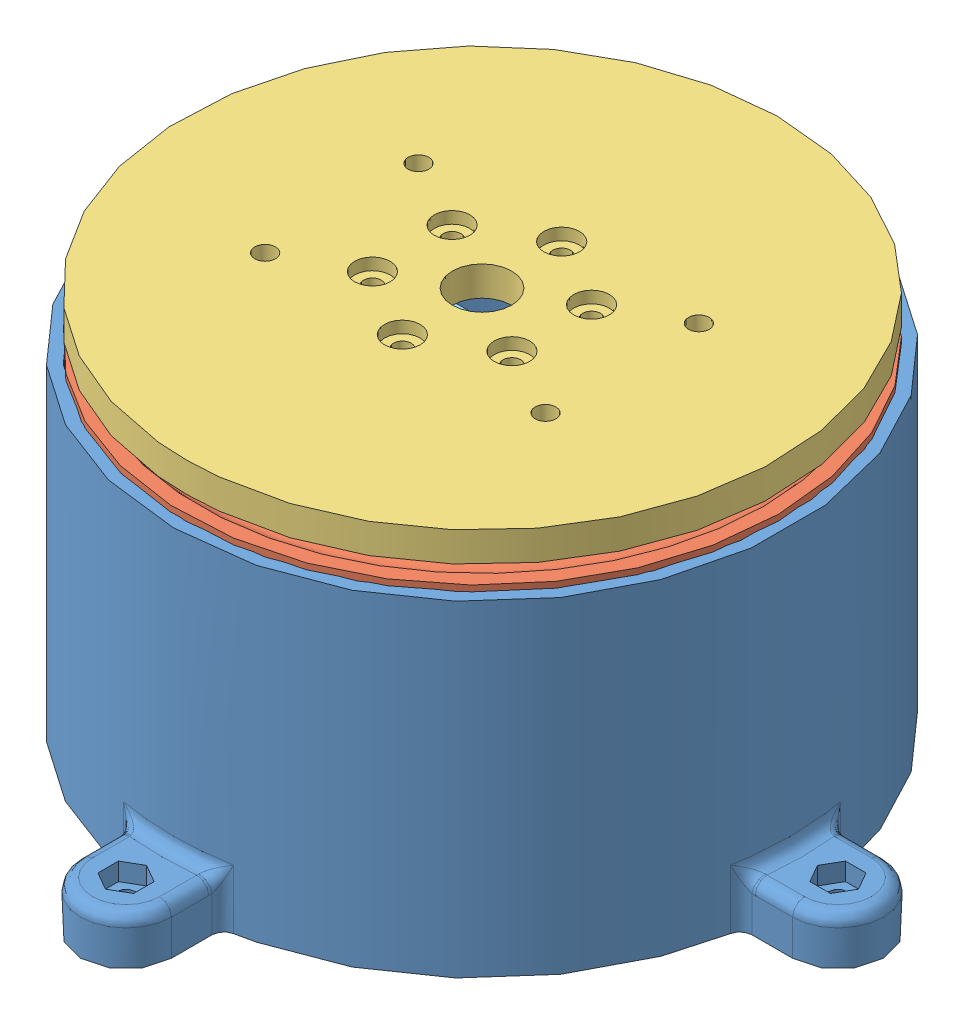
SolidWorks assembly AssemblyBase, configuration Default. Lengths in mm.
Overall size (135.31 64 135.31).
5 component instances, 5 part files, 10 mates.
Components (placement in the parent):
- CylindricCase-1: CylindricCase [Default] at origin size (135.31 55 135.31)
- BaseRing-1: BaseRing [Default] at (0 52 0) x (1 0 0) z (0 -1 0) size (100 100 4)
- BaseCap-1: BaseCap [Default] at (0 59 0) x (0.999984 0 -0.005612) z (0.005612 0 0.999984) size (100 5 100)
- MG995-1: MG995 [預設] at (-30.75 36.0463 9.75) size (54.5 43.19 19.5)
- InnerFastener-1: InnerFastener [Default] at (0 38.5863 0) x (-1 0 0) z (0 0 -1) size (94 5 94)
Mates (geometry in assembly coordinates):
- Концентричный1: concentric anti-aligned: cylinder of CylindricCase-1 through (0 69.6444 0) axis (0 1 0) radius 50; cylinder of BaseRing-1 through (0 52 0) axis (0 -1 0) radius 50
- Совпадение1: coincident anti-aligned: plane of CylindricCase-1 through (0 52 0) normal (0 1 0); plane of BaseRing-1 through (0 52 0) normal (0 -1 0)
- Концентричный2: concentric anti-aligned: cylinder of CylindricCase-1 through (0 69.6444 0) axis (0 1 0) radius 52; cylinder of BaseCap-1 through (0 64 0) axis (0 -1 0) radius 50
- Расстояние1: distance = 3 mm anti-aligned: plane of BaseCap-1 through (0 59 0) normal (0 -1 0); plane of BaseRing-1 through (0 56 0) normal (0 1 0)
- Совпадение4: coordinate: point of CylindricCase-1; point of assembly
- Концентричный3: concentric aligned: cylinder of BaseCap-1 through (0 64 0) axis (0 -1 0) radius 5; cylinder of MG995-1 through (0 52.2363 0) axis (0 -1 0) radius 2.925
- Параллельность1: parallel anti-aligned: plane of MG995-1 through (-30.75 44.5863 -9.75) normal (0 0 -1); plane of assembly through (0 0 0) normal (0 0 1)
- Концентричный4: concentric anti-aligned: cylinder of CylindricCase-1 through (0 69.6444 0) axis (0 1 0) radius 47; cylinder of InnerFastener-1 through (0 43.5863 0) axis (0 -1 0) radius 47
- Параллельность2: parallel anti-aligned: plane of MG995-1 through (-30.75 44.5863 -9.75) normal (0 0 -1); plane of InnerFastener-1 through (9.75 43.5863 -10) normal (0 0 1)
- Совпадение8: coincident anti-aligned: plane of MG995-1 through (9.75 38.5863 0.625) normal (0 1 0); plane of InnerFastener-1 through (0 38.5863 0) normal (0 -1 0)
